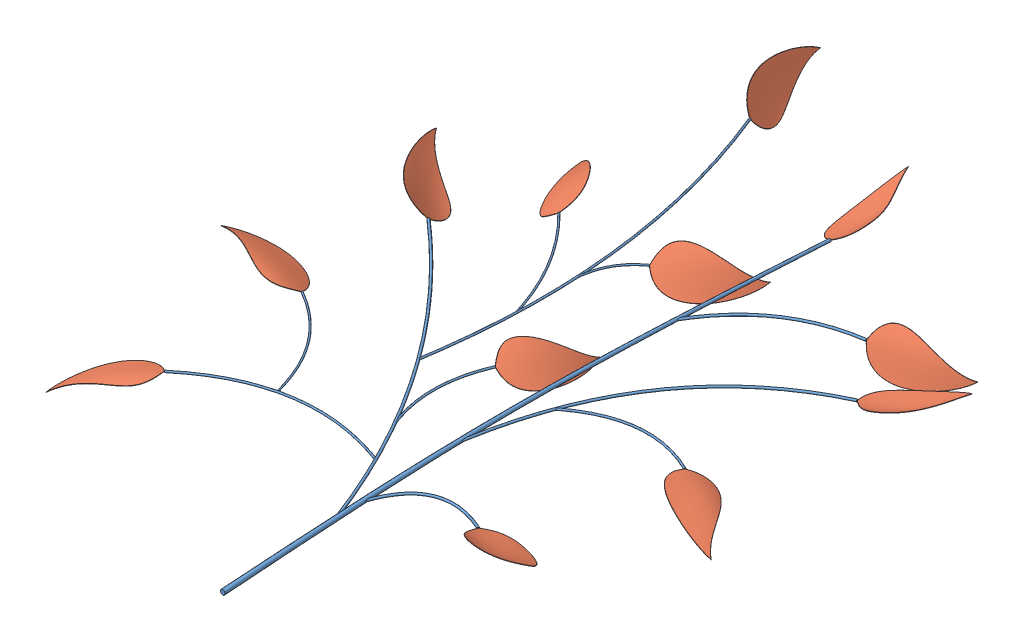
SolidWorks assembly Small Branch, configuration Default. Lengths in mm.
Overall size (314.27 42.14 439.71).
13 component instances, 2 part files, 24 mates.
Components (placement in the parent):
- Small Branch-1: Small Branch [Default] at origin size (214.34 2.87 387.61)
- Leaf-1: Leaf [Default] at (-126.8501 0 -93.2963) x (-0.636908 -0.142761 -0.757607) z (0.709104 0.277141 -0.648355) size (26.78 6 52.05)
- Leaf-2: Leaf [Default] at (-126.8501 0 -172.3953) x (-0.013277 -0.285636 -0.958246) z (0.991939 -0.124542 0.02338) size (26.78 6 52.05)
- Leaf-3: Leaf [Default] at (-126.8501 0 -245.0718) x (-0.525154 0.599129 0.604365) z (0.614609 -0.22419 0.756303) size (26.78 6 52.05)
- Leaf-4: Leaf [Default] at (-92.3172 0 -285.5855) x (0.533069 0.650396 -0.54113) z (0.556089 0.212694 0.803447) size (26.78 6 52.05)
- Leaf-5: Leaf [Default] at (-84.2583 0 -387.3824) x (-0.420387 0.890967 0.171619) z (0.131866 -0.127143 0.98308) size (26.78 6 52.05)
- Leaf-6: Leaf [Default] at (-40.2332 0 -285.5855) x (0.372303 -0.768109 0.520961) z (-0.655996 0.179296 0.73316) size (26.78 6 52.05)
- Leaf-7: Leaf [Default] at (-34.0505 0 -190.6428) x (0.783569 -0.523086 0.335262) z (-0.242974 0.238646 0.940219) size (26.78 6 52.05)
- Leaf-8: Leaf [Default] at (-0.8972 0 -350) x (-0.8697 -0.488533 -0.070406) z (0.058885 -0.244321 0.967905) size (26.78 6 52.05)
- Leaf-9: Leaf [Default] at (59.3764 0 -310.8062) x (0.063601 -0.898301 0.434754) z (-0.913477 0.123031 0.387844) size (26.78 6 52.05)
- Leaf-10: Leaf [Default] at (86.7887 0 -277.9973) x (-0.409978 -0.23426 -0.881499) z (-0.842796 -0.272218 0.46432) size (26.78 6 52.05)
- Leaf-11: Leaf [Default] at (71.4865 0 -194.3436) x (-0.415399 0.323221 0.850278) z (-0.822836 0.264979 -0.50272) size (26.78 6 52.05)
- Leaf-12: Leaf [Default] at (41.4889 0 -105.4654) x (0.385119 -0.368279 -0.8462) z (-0.916478 -0.260329 -0.303804) size (26.78 6 52.05)
Mates (geometry in assembly coordinates):
- Coincident3: coincident aligned: plane of Small Branch-1 through (-126.517 -0.0162 -92.9001) normal (-0.765447 0 0.643499); circle of Leaf-1
- Coincident4: coincident: curve of Small Branch-1; point of Leaf-1
- Coincident5: coincident: point of Small Branch-1; point of Leaf-2
- Tangent4: tangent: face of Small Branch-1; circle of Leaf-2
- Coincident10: coincident: point of Small Branch-1; point of Leaf-3
- Coincident11: coincident aligned: plane of Small Branch-1 through (-127.2696 -0.0303 -244.589) normal (-0.754841 0 -0.655908); circle of Leaf-3
- Coincident12: coincident aligned: plane of Small Branch-1 through (-92.6169 -0.0145 -285.2812) normal (-0.712393 0 -0.701781); circle of Leaf-4
- Coincident13: coincident: point of Small Branch-1; point of Leaf-4
- Coincident14: coincident aligned: plane of Small Branch-1 through (-84.7476 -0.0555 -387.1827) normal (-0.377959 0 -0.925822); circle of Leaf-5
- Coincident15: coincident: point of Small Branch-1; point of Leaf-5
- Coincident16: coincident aligned: plane of Small Branch-1 through (-40.4771 -0.0367 -285.9268) normal (0.813595 0 -0.581432); circle of Leaf-6
- Coincident17: coincident: point of Small Branch-1; point of Leaf-6
- Coincident18: coincident: point of Small Branch-1; point of Leaf-7
- Coincident19: coincident aligned: plane of Small Branch-1 through (-34.5369 0.0055 -190.8509) normal (0.39337 0 -0.91938); circle of Leaf-7
- Coincident20: coincident aligned: plane of Small Branch-1 through (-1.6538 0.1105 -350.0612) normal (0.080691 0 -0.996739); circle of Leaf-8
- Coincident21: coincident: point of Small Branch-1; point of Leaf-8
- Coincident22: coincident aligned: plane of Small Branch-1 through (59.3717 -0.6276 -310.8383) normal (0.989468 0 -0.144751); circle of Leaf-9
- Coincident23: coincident: point of Small Branch-1; point of Leaf-9
- Coincident24: coincident aligned: plane of Small Branch-1 through (86.7894 -0.623 -277.9959) normal (0.90673 0 -0.421713); circle of Leaf-10
- Coincident25: coincident: point of Small Branch-1; point of Leaf-10
- Coincident26: coincident aligned: plane of Small Branch-1 through (71.5049 -0.5493 -194.3814) normal (0.898506 0 0.43896); circle of Leaf-11
- Coincident27: coincident: point of Small Branch-1; point of Leaf-11
- Coincident28: coincident: point of Small Branch-1; point of Leaf-12
- Coincident29: coincident aligned: plane of Small Branch-1 through (41.7549 -0.0223 -106.0499) normal (0.910171 0 0.414233); circle of Leaf-12
